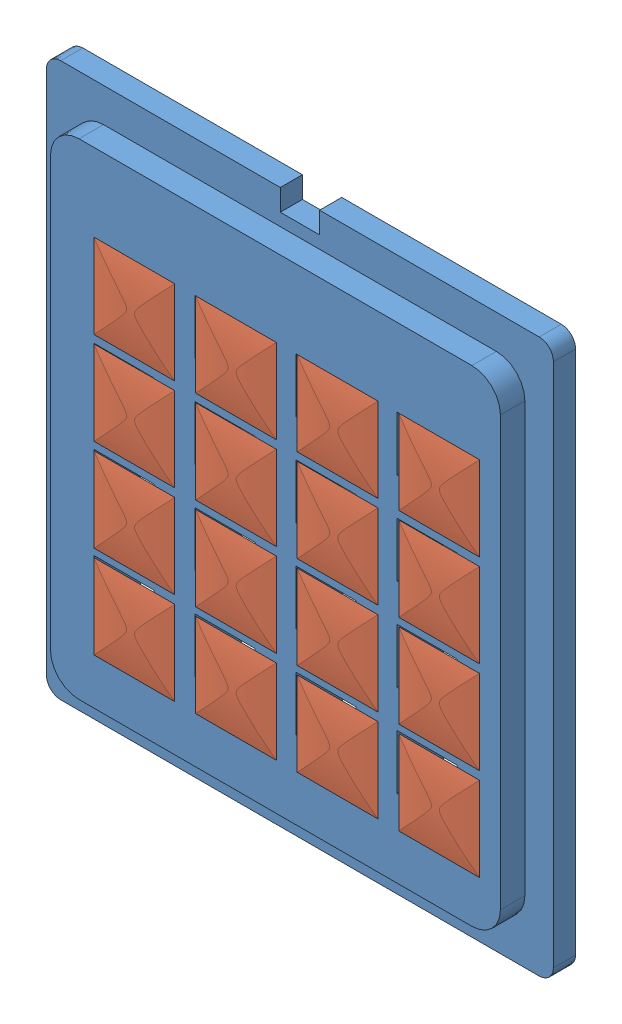
SolidWorks assembly box_keypad, configuration Default. Lengths in mm.
Overall size (71 77.5 8.56).
17 component instances, 2 part files, 4 mates.
Components (placement in the parent):
- plastic_base-1: plastic_base [Default] at (-16.436 8.6289 2.8107) size (71 77.5 6.53)
- key-1: key [Default] at (-36.186 25.8429 9.3385) size (11.84 11.8 0.8)
- key-2: key [Default] at (-36.186 12.8889 9.3385) size (11.84 11.8 0.8)
- key-3: key [Default] at (-36.186 -0.0651 9.3385) size (11.84 11.8 0.8)
- key-4: key [Default] at (-36.186 -13.0191 9.3385) size (11.84 11.8 0.8)
- key-5: key [Default] at (-21.962 25.8429 9.3385) size (11.84 11.8 0.8)
- key-6: key [Default] at (-21.962 12.8889 9.3385) size (11.84 11.8 0.8)
- key-7: key [Default] at (-21.962 -0.0651 9.3385) size (11.84 11.8 0.8)
- key-8: key [Default] at (-21.962 -13.0191 9.3385) size (11.84 11.8 0.8)
- key-9: key [Default] at (-7.738 25.8429 9.3385) size (11.84 11.8 0.8)
- key-10: key [Default] at (-7.738 12.8889 9.3385) size (11.84 11.8 0.8)
- key-11: key [Default] at (-7.738 -0.0651 9.3385) size (11.84 11.8 0.8)
- key-12: key [Default] at (-7.738 -13.0191 9.3385) size (11.84 11.8 0.8)
- key-13: key [Default] at (6.486 25.8429 9.3385) size (11.84 11.8 0.8)
- key-14: key [Default] at (6.486 12.8889 9.3385) size (11.84 11.8 0.8)
- key-15: key [Default] at (6.486 -0.0651 9.3385) size (11.84 11.8 0.8)
- key-16: key [Default] at (6.486 -13.0191 9.3385) size (11.84 11.8 0.8)
Mates (geometry in assembly coordinates):
- Distance1: distance = 0.127 mm aligned: plane of ? through (91.7261 -90.711 2.6837) normal (0 0 -1); plane of plastic_base-1 through (-16.436 8.6289 2.8107) normal (0 0 -1)
- Coincident7: coincident anti-aligned: plane of plastic_base-1 through (-43.936 38.6289 9.3385) normal (0 0 1); plane of key-1 through (-41.836 19.9429 9.3385) normal (0 0 -1)
- Coincidente1: coincident aligned: line of plastic_base-1 through (-19.3138 31.7429 9.3385) axis (-1 0 0); line of key-5 through (-16.312 31.7429 9.3385) axis (-1 0 0)
- Coincidente2: coincident aligned: line of plastic_base-1 through (-41.836 31.7429 9.3385) axis (0 -1 0); line of key-1 through (-41.836 31.7429 9.3385) axis (0 -1 0)
